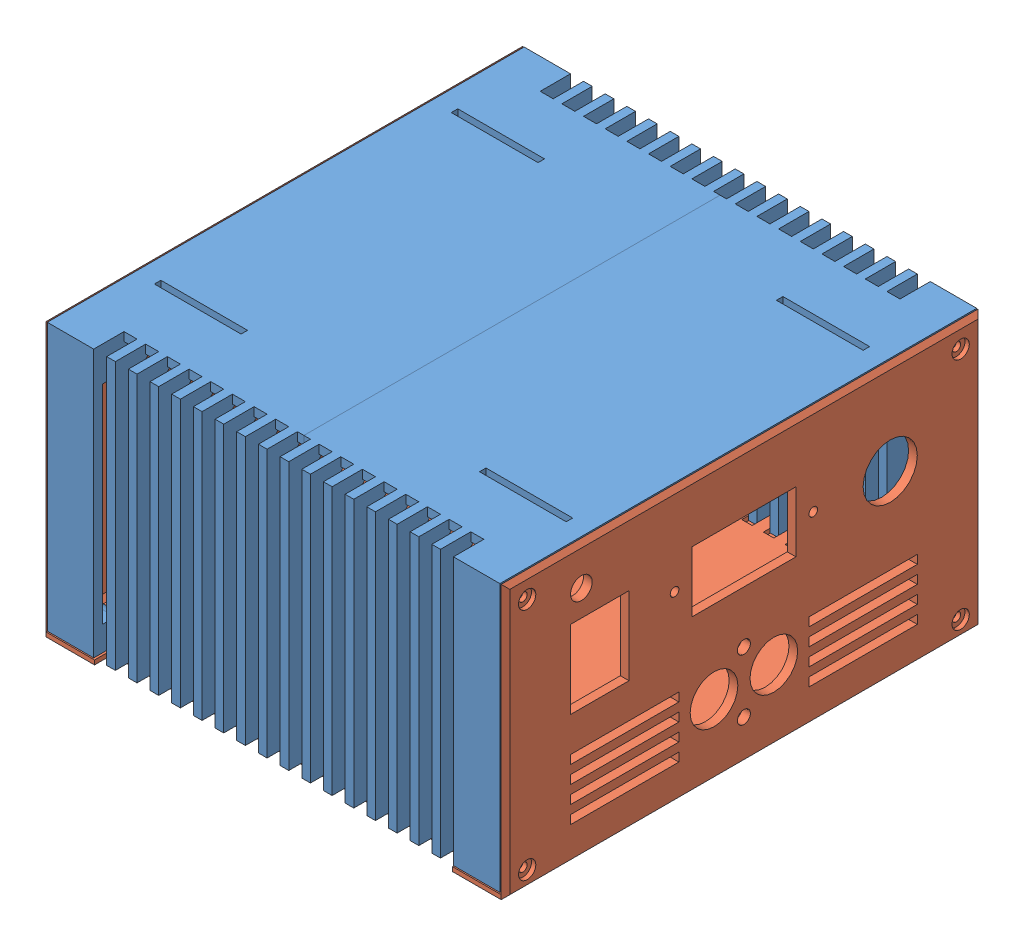
SolidWorks assembly Assembly, configuration Default. Lengths in mm.
Overall size (107 63.01 110).
2 component instances, 2 part files, 2 mates.
Components (placement in the parent):
- P2_new-1: P2_new [Default] at (29.4251 63.7556 86.2589) size (104.4 61.7 110)
- P1_new-2: P1_new [Default] at (102.3294 59.4019 203.4541) x (0 0 -1) z (1 0 0) size (110 63 107)
Mates (geometry in assembly coordinates):
- Coincident1: coincident: plane of P2_new-1 through (-4.6706 61.4086 203.4541) normal (-1 0 0); plane of P1_new-2 through (-4.6706 61.3795 203.4541) normal (1 0 0)
- Coincident2: coincident aligned: plane of P2_new-1 through (-4.6706 61.4086 93.4541) normal (0 0 -1); plane of P1_new-2 through (8.3294 59.4019 93.4541) normal (0 0 -1)
